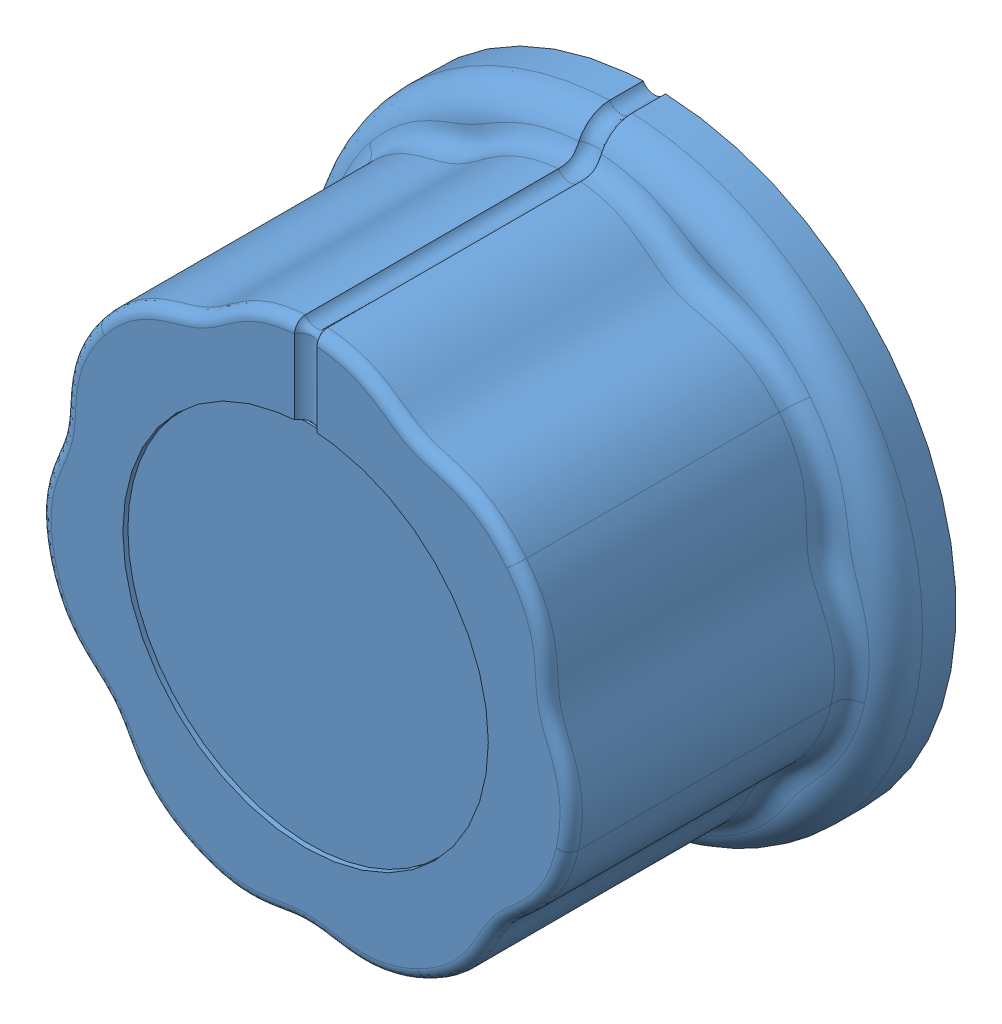
SolidWorks assembly Pointer Knob WTN-15, configuration Default. Lengths in mm.
Overall size (27 27.07 15.83).
2 component instances, 2 part files, 2 mates.
Components (placement in the parent):
- Pointer Knob WTN-15-1: Pointer Knob WTN-15 [Default] at origin size (27 27.07 15.83)
- socket set screw flat point_am-2: socket set screw flat point_am [B18.3.6M - M4 x 0.7 x 8 Hex Socket Flat Pt. SS --N] at (0 -10.2 7.85) x (0 1 0) z (0 0 1) size (8 4 4)
Mates (geometry in assembly coordinates):
- Concentric1: concentric aligned: cylinder of Pointer Knob WTN-15-1 through (0 -12 7.85) axis (0 -1 0) radius 2; cylinder of socket set screw flat point_am-2 through (0 -22.9 7.85) axis (0 -1 0) radius 2
- Distance1: distance = 1 mm anti-aligned: plane of socket set screw flat point_am-2 through (-1.25 -2.2 7.85) normal (0 1 0); cylinder of Pointer Knob WTN-15-1 through (0 0 3.1) axis (0 0 -1) radius 3.2
